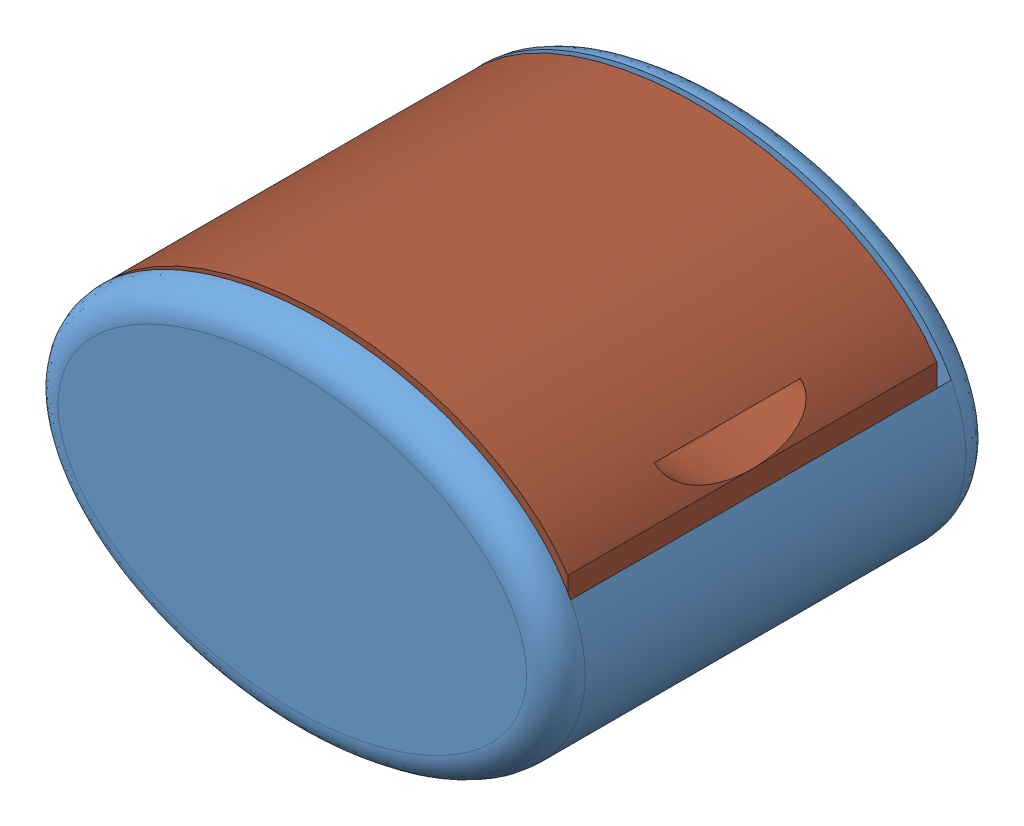
SolidWorks assembly Velcro Assembly, configuration Default. Lengths in mm.
Overall size (49.71 34.45 38.1).
30 component instances, 11 part files, 10 mates.
Components (placement in the parent):
- Bottom-1: Bottom [Default] at (-4.0747 21.0508 34.2156) size (49.71 34.45 38.1)
- Flashlight PCB 2-1: Flashlight PCB 2 [Default] at (-19.3987 16.296 36.6032) x (1 0 0) z (0 -1 0) size (33.81 35.83 17.34)
  - Board-1: Board [Default] at origin size (28.59 32.39 0.41)
  - U1-1: U1 [Default] at origin size (3.01 2.91 1.23)
    - SOT23-3-1: SOT23-3 [Default] at (15.3909 26.7763 0) x (0 -1 0) z (0 0 1) size (2.91 3.01 1.23)
    - 4438511424-1: 4438511424 [Default] at (15.494 27.051 0) size (0.25 0.25 0.25)
      - Extruded-1: Extruded [Default] at origin size (0.25 0.25 0.25)
  - R3-1: R3 [Default] at origin size (0.95 1.7 0.9)
    - 4438511040-1: 4438511040 [Default] at (19.685 10.656 0) size (0.95 1.7 0.9)
      - Extruded_2-1: Extruded_2 [Default] at origin size (0.95 1.7 0.9)
  - R2-1: R2 [Default] at origin size (0.95 1.7 0.9)
    - 4438511040-1: 4438511040 [Default] at (17.526 10.656 0) size (0.95 1.7 0.9)
      - Extruded_2-1: Extruded_2 [Default] at origin size (0.95 1.7 0.9)
  - R1-1: R1 [Default] at origin size (0.95 1.7 0.9)
    - 4438511040-1: 4438511040 [Default] at (11.442 10.656 0) size (0.95 1.7 0.9)
      - Extruded_2-1: Extruded_2 [Default] at origin size (0.95 1.7 0.9)
  - R4-1: R4 [Default] at origin size (1.7 0.95 0.9)
    - 4438510848-1: 4438510848 [Default] at (19.443 13.716 0) size (1.7 0.95 0.9)
      - Extruded_3-1: Extruded_3 [Default] at origin size (1.7 0.95 0.9)
  - C2-1: C2 [Default] at origin size (0.95 1.75 1.3)
    - 4438511232-1: 4438511232 [Default] at (12.7 27.748 0) size (0.95 1.75 1.3)
      - Extruded_4-1: Extruded_4 [Default] at origin size (0.95 1.75 1.3)
  - C1-1: C1 [Default] at origin size (1.75 0.95 1.3)
    - 4438510656-1: 4438510656 [Default] at (15.24 23.684 0) size (1.75 0.95 1.3)
      - Extruded_5-1: Extruded_5 [Default] at origin size (1.75 0.95 1.3)
  - ATTiny85-1: ATTiny85 [Default] at origin size (8.25 5.36 2.16)
    - 8S2-1: 8S2 [Default] at (20.8151 20.955 0) x (0 1 0) z (0 0 1) size (8.25 5.36 2.16)
  - Imported-1: Imported [Default] at origin size (27.76 30.96 17.34)
    - keystone-PN1025-7-1: keystone-PN1025-7 [Default] at (15.3925 15.0498 -2.9515) x (1 0 0) z (0 1 0) size (27.76 17.34 30.96)
- Top-1: Top [Default] at (-4.0747 21.0508 34.2156) size (42.12 13.11 32)
Mates (geometry in assembly coordinates):
- Parallel10: parallel anti-aligned: plane of Bottom-1 through (-4.0747 21.0508 69.7756) normal (0 0 -1); plane of Flashlight PCB 2-1/Board-1 through (-18.2557 16.7074 69.7502) normal (0 0 1)
- Distance1: distance = 0.508 mm: plane of Top-1 through (-4.0747 38.2994 69.2676) normal (0 0 1); plane of Bottom-1 through (-4.0747 21.0508 69.7756) normal (0 0 -1)
- Parallel11: parallel: plane of Bottom-1 through (-4.0747 21.0508 69.7756) normal (0 0 -1); plane of Top-1 through (-4.0747 82.3726 69.2676) normal (0 0 1)
- Parallel12: parallel: plane of Bottom-1 through (17.5153 21.0508 69.7756) normal (-1 0 0); plane of Top-1 through (16.7822 82.3726 34.2156) normal (1 0 0)
- Parallel13: parallel anti-aligned: plane of Bottom-1 through (-4.0747 21.0508 69.7756) normal (0 0 -1); plane of Flashlight PCB 2-1/Board-1 through (-18.2557 16.7074 69.7502) normal (0 0 1)
- Distance3: distance = 0.0254 mm anti-aligned: plane of Bottom-1 through (-4.0747 21.0508 69.7756) normal (0 0 -1); plane of Flashlight PCB 2-1/Board-1 through (-18.2557 16.7074 69.7502) normal (0 0 1)
- Parallel14: parallel anti-aligned: plane of Bottom-1 through (-18.6797 12.1608 36.7556) normal (1 0 0); plane of Flashlight PCB 2-1/Board-1 through (-18.2987 16.7074 51.7162) normal (-1 0 0)
- Distance4: distance = 0.381 mm anti-aligned: plane of Flashlight PCB 2-1/Board-1 through (-18.2987 16.7074 51.7162) normal (-1 0 0); plane of Bottom-1 through (-18.6797 12.1608 36.7556) normal (1 0 0)
- Distance5: distance = 0 mm: plane of Top-1 through (10.5303 12.1608 36.7556) normal (-1 0 0); plane of Bottom-1 through (10.5303 12.1608 36.7556) normal (-1 0 0)
- Distance6: distance = 17.78 mm anti-aligned: plane of Bottom-1 through (10.5303 12.1608 36.7556) normal (0 1 0); plane of Top-1 through (10.5303 29.9408 36.7556) normal (0 -1 0)
